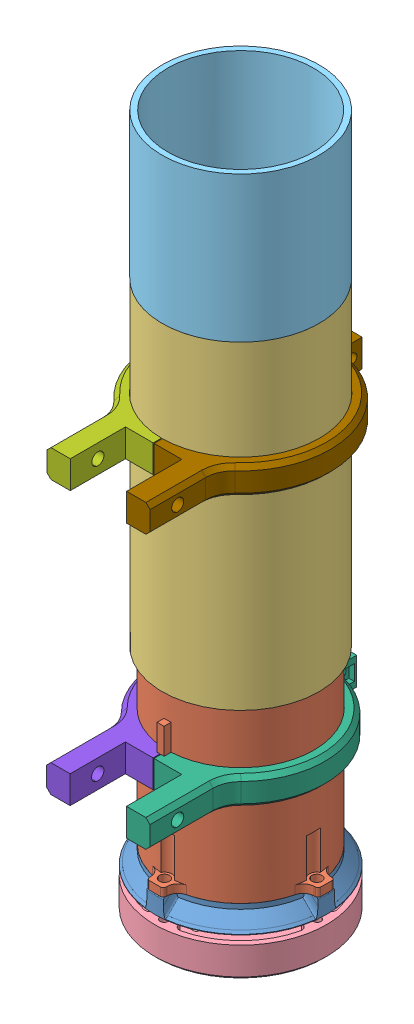
SolidWorks assembly Guidescope, configuration Standard. Lengths in mm.
Overall size (78.97 250.93 91.05).
9 component instances, 9 part files, 25 mates.
Components (placement in the parent):
- 01_camera_mount_v3-1: 01_camera_mount_v3 [Standard] at (4.0018 -14.9462 64.2361) size (65.7 15 65.7)
- 02_scope_mid_v3-1: 02_scope_mid_v3 [Standard] at (4.0018 90.6538 64.2361) x (1 0 0) z (0 -1 0) size (62.23 62.23 100.55)
- 03_scope_front_v4-1: 03_scope_front_v4 [Standard] at (4.0018 178.0538 64.2361) x (-0.824538 0 0.565807) z (0.565807 0 0.824538) size (56.8 125.87 56.8)
- 04_camera_lid_v3-1: 04_camera_lid_v3 [Standard] at (4.0018 -19.1245 64.2361) x (-1 0 0) z (0 0 1) size (62.23 11 62.23)
- 09_lens_hood-1: 09_lens_hood [Standard] at (4.0018 168.0538 64.2361) x (0.924318 0 -0.381623) z (0 1 0) size (56.8 56.89 53.2)
- guider_attachment_back_1-1: guider_attachment_back_1 [Standard] at (4.0018 23.3036 64.2361) x (-1 0 0) z (0 1 0) size (30.4 89.1 10)
- guider_attachment_front_1-1: guider_attachment_front_1 [Standard] at (4.0018 132.0775 64.2361) x (1 0 0) z (0 -1 0) size (32.35 91 10)
- guider_attachment_back_2-1: guider_attachment_back_2 [Standard] at (4.0018 33.3036 64.2361) x (1 0 0) z (0 -1 0) size (30.4 89.1 10)
- guider_attachment_front_2-1: guider_attachment_front_2 [Standard] at (4.0018 132.0775 64.2361) x (1 0 0) z (0 -1 0) size (32.35 91 10)
Mates (geometry in assembly coordinates):
- Konzentrisch1: concentric anti-aligned: cylinder of 01_camera_mount_v3-1 through (4.0018 -0.9462 64.2361) axis (0 -1 0) radius 24.7; cylinder of 02_scope_mid_v3-1 through (4.0018 -9.3462 64.2361) axis (0 1 0) radius 24.9
- Konzentrisch3: concentric aligned: cylinder of 02_scope_mid_v3-1 through (4.0018 -9.3462 64.2361) axis (0 1 0) radius 24.9; cylinder of 03_scope_front_v4-1 through (4.0018 52.5538 64.2361) axis (0 1 0) radius 26.9
- Konzentrisch4: concentric: cylinder of 01_camera_mount_v2-1 through (-23.9573 -15.9462 64.2361) axis (0 1 0) radius 1.725; cylinder of 04_camera_lid_v3TI-1 through (-23.6038 -28.5401 64.2361) axis (0 1 0) radius 2.15
- Konzentrisch11: concentric anti-aligned: cylinder of 03_scope_front_v4-1 through (4.0018 167.5538 64.2361) axis (0 1 0) radius 26.25; cylinder of 09_lens_hood-1 through (4.0018 220.8038 64.2361) axis (0 -1 0) radius 26.375
- Deckungsgleich24: coincident anti-aligned: plane of 01_camera_mount_v3-1 through (4.0018 -9.3462 64.2361) normal (0 1 0); plane of 02_scope_mid_v3-1 through (4.0018 -9.3462 64.2361) normal (0 -1 0)
- Abstand1: distance = 182 mm aligned: plane of 03_scope_front_v3-1 through (4.0018 168.0538 64.2361) normal (0 1 0); plane of 01_camera_mount_v2-1 through (4.0018 -14.9462 64.2361) normal (0 1 0)
- Konzentrisch12: concentric anti-aligned: cylinder of 02_scope_mid_v3-1 through (4.0018 -9.3462 64.2361) axis (0 1 0) radius 26.5; cylinder of guider_attachment_back_1-1 through (4.0018 33.3036 64.2361) axis (0 -1 0) radius 26.55
- Konzentrisch13: concentric anti-aligned: cylinder of 03_scope_front_v4-1 through (4.0018 168.0538 64.2361) axis (0 -1 0) radius 28.4; cylinder of guider_attachment_front_1-1 through (4.0018 122.0775 64.2361) axis (0 1 0) radius 28.5
- Deckungsgleich25: coincident aligned: plane of guider_attachment_back-1 through (-14.6982 19.2649 115.9361) normal (-1 0 0); plane of guider_attachment_front-1 through (-14.6982 122.2754 115.7361) normal (-1 0 0)
- Parallel1: parallel: line of 01_camera_mount_v2-1 through (-8.2524 -15.9462 51.0861) axis (1 0 0); plane of guider_attachment_back-1 through (14.2018 19.2649 95.9361) normal (0 0 1)
- Deckungsgleich26: coincident aligned: plane of 01_camera_mount_v2-1 through (4.0018 -14.9462 64.2361) normal (1 0 0); plane of 02_scope_mid_v3-1
- Konzentrisch14: concentric aligned: cylinder of 04_camera_lid_v3-1 through (4.0018 -29.1245 64.2361) axis (0 1 0) radius 31.1127; circle of 01_camera_mount_v3-1
- Deckungsgleich27: coincident anti-aligned: plane of 03_scope_front_v4-1 through (4.0018 168.0538 64.2361) normal (0 1 0); plane of 09_lens_hood-1 through (4.0018 168.0538 64.2361) normal (0 -1 0)
- Konzentrisch16: concentric aligned: cylinder of 02_scope_mid_v3-1 through (4.0018 -9.3462 64.2361) axis (0 1 0) radius 26.5; cylinder of guider_attachment_back_2-1 through (4.0018 23.3036 64.2361) axis (0 1 0) radius 26.55
- Deckungsgleich28: coincident anti-aligned: plane of guider_attachment_back_1-1 through (4.0018 29.6336 64.2361) normal (-1 0 0); plane of guider_attachment_back_2-1 through (4.0018 19.6336 64.2361) normal (1 0 0)
- Deckungsgleich29: coincident aligned: plane of guider_attachment_back_1-1 through (4.0018 23.3036 64.2361) normal (0 -1 0); plane of guider_attachment_back_2-1 through (4.0018 23.3036 64.2361) normal (0 -1 0)
- Konzentrisch17: concentric: cylinder of 01_camera_mount_v2-1 through (4.0018 -15.9462 92.1953) axis (0 1 0) radius 1.725; cylinder of 02_scope_mid_v3-1 through (4.0018 -6.3462 91.8417) axis (0 -1 0) radius 1.85
- Parallel2: parallel aligned: plane of 02_scope_mid_v3-1 through (2.7518 42.6538 90.7361) normal (-1 0 0); plane of guider_attachment_back_1-1 through (14.2018 33.3036 95.7861) normal (-1 0 0)
- Parallel3: parallel aligned: plane of guider_attachment_back_1-1 through (14.2018 28.9779 95.7861) normal (-1 0 0); plane of guider_attachment_front-1 through (14.2018 122.0682 95.7361) normal (-1 0 0)
- Konzentrisch18: concentric anti-aligned: cylinder of 03_scope_front_v4-1 through (4.0018 168.0538 64.2361) axis (0 -1 0) radius 28.4; cylinder of guider_attachment_front_2-1 through (4.0018 122.0775 64.2361) axis (0 1 0) radius 28.5
- Deckungsgleich30: coincident aligned: plane of guider_attachment_front_1-1 through (4.0018 122.0775 64.2361) normal (0 -1 0); plane of guider_attachment_front_2-1 through (4.0018 122.0775 64.2361) normal (0 -1 0)
- Parallel4: parallel anti-aligned: plane of guider_attachment_front_1-1 through (3.8518 122.0775 91.7147) normal (1 0 0); plane of guider_attachment_front_2-1 through (4.1518 122.0775 96.4445) normal (-1 0 0)
- Parallel5: parallel aligned: plane of guider_attachment_back_1-1 through (14.2018 33.3036 95.7861) normal (-1 0 0); plane of guider_attachment_front_2-1 through (14.2018 122.0775 95.7361) normal (-1 0 0)
- Abstand2: distance = 183 mm aligned: plane of 03_scope_front_v4-1 through (4.0018 168.0538 64.2361) normal (0 1 0); plane of 01_camera_mount_v3-1 through (4.0018 -14.9462 64.2361) normal (0 1 0)
- Konzentrisch19: concentric aligned: cylinder of 01_camera_mount_v3-1 through (4.0018 -15.9462 36.5234) axis (0 1 0) radius 1.8; cylinder of 04_camera_lid_v3-1 through (4.0018 -29.1245 36.5234) axis (0 1 0) radius 1.425
